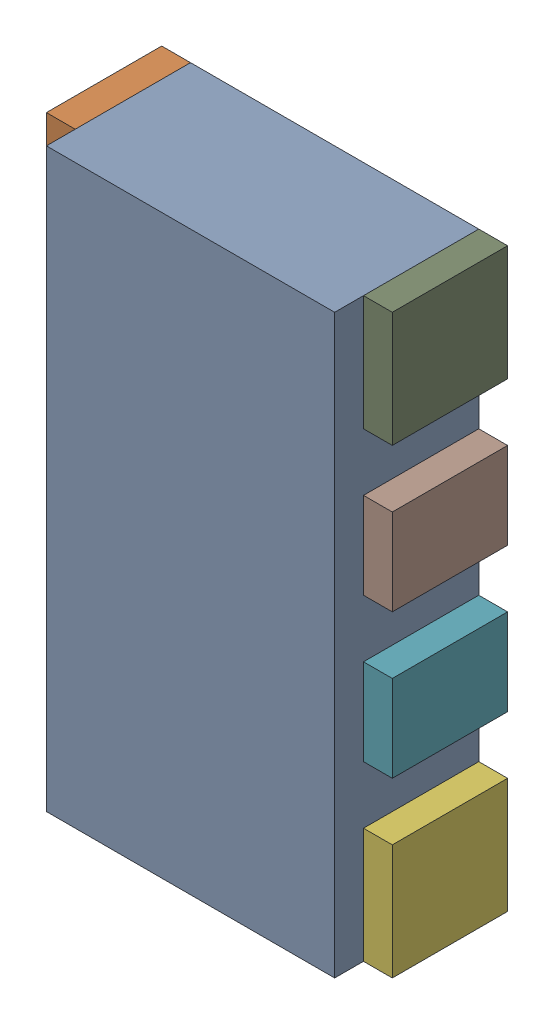
SolidWorks assembly RN8, configuration Default. Lengths in mm.
Overall size (1.2 2 0.5).
18 component instances, 3 part files, 0 mates.
Components (placement in the parent):
- 836750320-1: 836750320 [Default] at (115.5 42.65 0) size (1 2 0.5)
  - Extruded_15-1: Extruded_15 [Default] at origin size (1 2 0.5)
- 791587232-1: 791587232 [Default] at (114.95 43.45 0) size (0.1 0.4 0.4)
  - Extruded_10-1: Extruded_10 [Default] at origin size (0.1 0.4 0.4)
- 836750576-1: 836750576 [Default] at (114.95 42.9 0) size (0.1 0.3 0.4)
  - Extruded_14-1: Extruded_14 [Default] at origin size (0.1 0.3 0.4)
- 836750576-2: 836750576 [Default] at (114.95 42.4 0) size (0.1 0.3 0.4)
  - Extruded_14-1: Extruded_14 [Default] at origin size (0.1 0.3 0.4)
- 791587232-2: 791587232 [Default] at (114.95 41.85 0) size (0.1 0.4 0.4)
  - Extruded_10-1: Extruded_10 [Default] at origin size (0.1 0.4 0.4)
- 791587232-3: 791587232 [Default] at (116.05 41.85 0) size (0.1 0.4 0.4)
  - Extruded_10-1: Extruded_10 [Default] at origin size (0.1 0.4 0.4)
- 836750576-3: 836750576 [Default] at (116.05 42.4 0) size (0.1 0.3 0.4)
  - Extruded_14-1: Extruded_14 [Default] at origin size (0.1 0.3 0.4)
- 836750576-4: 836750576 [Default] at (116.05 42.9 0) size (0.1 0.3 0.4)
  - Extruded_14-1: Extruded_14 [Default] at origin size (0.1 0.3 0.4)
- 791587232-4: 791587232 [Default] at (116.05 43.45 0) size (0.1 0.4 0.4)
  - Extruded_10-1: Extruded_10 [Default] at origin size (0.1 0.4 0.4)
